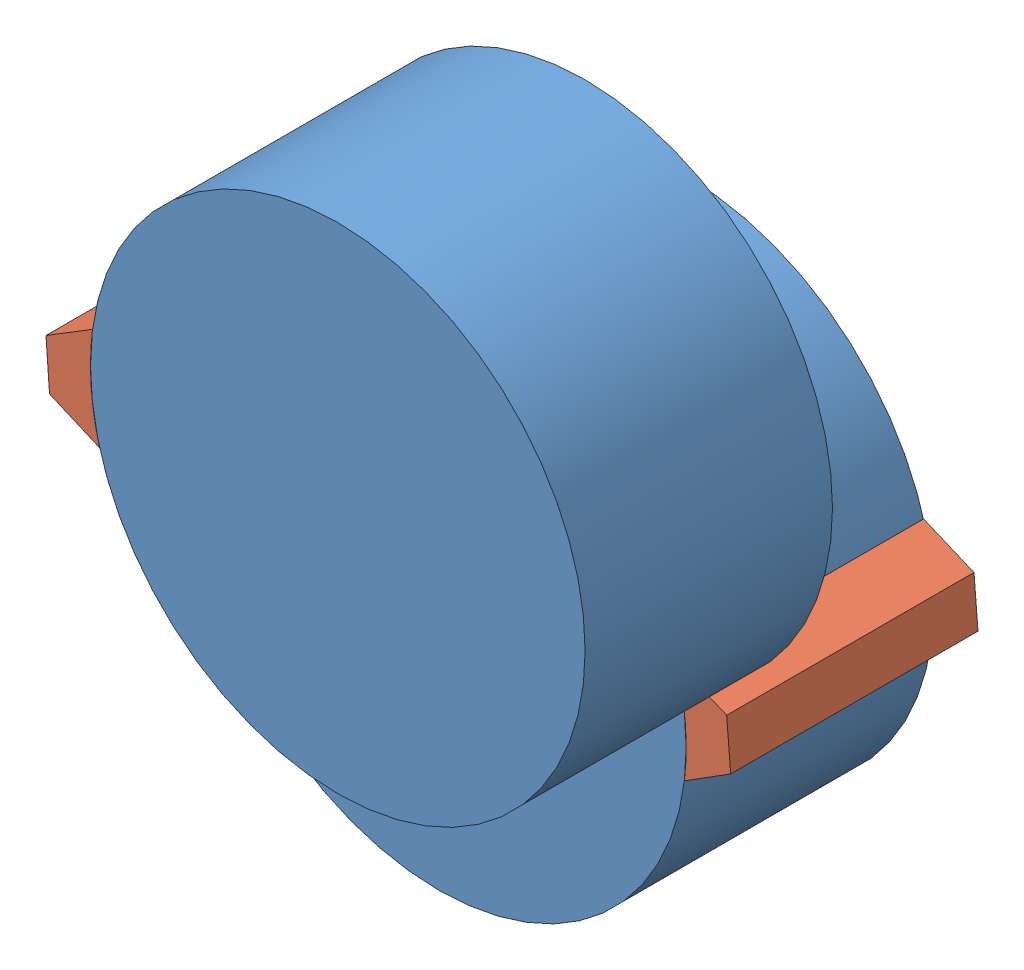
SolidWorks assembly Assem3, configuration Default. Lengths in mm.
Overall size (26.17 31.59 20.25).
4 component instances, 2 part files, 5 mates.
Components (placement in the parent):
- Part2-1: Part2 [Default] at (6.1687 11.5902 10.2526) size (20 20 10)
- Part3-1: Part3 [Default] at (6.1687 11.5902 10.2526) x (-0.071492 0.997441 0) z (0 0 1) size (4.02 1.96 10)
- Part2-2: Part2 [Default] at origin size (20 20 10)
- Part3-2: Part3 [Default] x (0.081546 -0.99667 0) z (0 0 1) size (4.02 1.96 10)
Mates (geometry in assembly coordinates):
- Concentric1: concentric aligned: cylinder of Part2-1 through (6.1687 11.5902 20.2526) axis (0 0 -1) radius 10; cylinder of Part3-1 through (6.1687 11.5902 20.2526) axis (0 0 -1) radius 10
- Coincident1: coincident aligned: plane of Part2-1 through (6.1687 11.5902 20.2526) normal (0 0 1); plane of Part3-1 through (6.1687 11.5902 20.2526) normal (0 0 1)
- Coincident3: coordinate: point of assembly; point of Part2-2; point of assembly
- Concentric2: concentric: cylinder of Part2-2 through (0 0 10) axis (0 0 -1) radius 10; cylinder of Part3-2 through (0 0 10) axis (0 0 -1) radius 10
- Coincident4: coincident: plane of Part2-2 through (0 0 0) normal (0 0 -1); plane of Part3-2 through (0 0 0) normal (0 0 -1)
